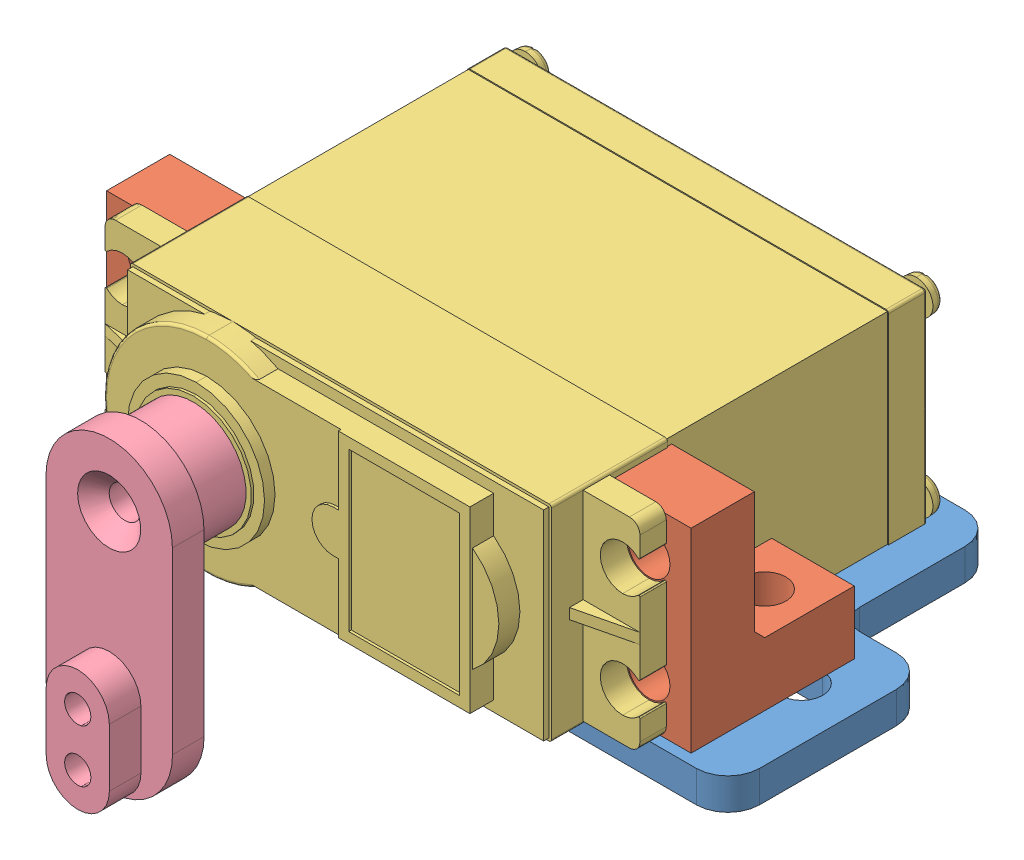
SolidWorks assembly Servo_mount, configuration Default. Lengths in mm.
Overall size (60 32.83 56.75).
5 component instances, 4 part files, 10 mates.
Components (placement in the parent):
- Servo_mount_1-1: Servo_mount_1 [Default] at origin size (60 3 34)
- Servo_mount_2-1: Servo_mount_2 [Default] at (-21 3 0.5) x (-1 0 0) z (0 0 -1) size (8 18.5 15.5)
- Servo_mount_2-2: Servo_mount_2 [Default] at (26.5 3 0.5) x (-1 0 0) z (0 0 -1) size (8 18.5 15.5)
- Servo-1: Servo [Default] at (-1.25 12.5 21.5) x (0 -1 0) z (0 0 -1) size (19.65 50.8 49.75)
- Servo_shaft-1: Servo_shaft [Default] at (-11.4931 4 30.25) x (0.000814 -1 0) z (-1 -0.000814 0) size (29 11 12)
Mates (geometry in assembly coordinates):
- Concentric1: concentric anti-aligned: cylinder of Servo_mount_1-1 through (-25 3 5) axis (0 -1 0) radius 2; cylinder of Servo_mount_2-1 through (-25 3 5) axis (0 1 0) radius 2
- Coincident1: coincident anti-aligned: plane of Servo_mount_1-1 through (0 3 0) normal (0 1 0); plane of Servo_mount_2-1 through (-29 3 0.5) normal (0 -1 0)
- Coincident2: coincident anti-aligned: plane of Servo_mount_1-1 through (0 3 0) normal (0 1 0); plane of Servo_mount_2-2 through (18.5 3 0.5) normal (0 -1 0)
- Coincident3: coincident aligned: plane of Servo_mount_2-1 through (-29 3 16) normal (0 0 1); plane of Servo_mount_2-2 through (18.5 3 16) normal (0 0 1)
- Coincident4: coincident aligned: plane of Servo_mount_1-1 through (-29 3 0) normal (-1 0 0); plane of Servo_mount_2-1 through (-29 3 0.5) normal (-1 0 0)
- Concentric4: concentric anti-aligned: cylinder of Servo_shaft-1 through (-11.5 12.5 33.25) axis (0 0 -1) radius 1.5; cylinder of Servo-1 through (-11.5 12.5 29.25) axis (0 0 1) radius 0.8
- Coincident6: coincident: plane of assembly; plane of Servo-1 through (-11.5 12.5 29.25) normal (0 0 1); plane of Servo_shaft-1 through (-11.4931 4 29.25) normal (0 0 -1)
- Concentric5: concentric aligned: cylinder of Servo_mount_2-1 through (-25 17.5 4.3431) axis (0 0 1) radius 2; cylinder of Servo-1 through (-25 17.5 16) axis (0 0 1) radius 2.125
- Concentric6: concentric aligned: cylinder of Servo_mount_2-2 through (22.5 17.5 4.3431) axis (0 0 1) radius 2; cylinder of Servo-1 through (22.5 17.5 16) axis (0 0 1) radius 2.125
- Coincident8: coincident anti-aligned: plane of Servo_mount_2-2 through (18.5 3 16) normal (0 0 1); plane of Servo-1 through (23.1466 21 16) normal (0 0 -1)
